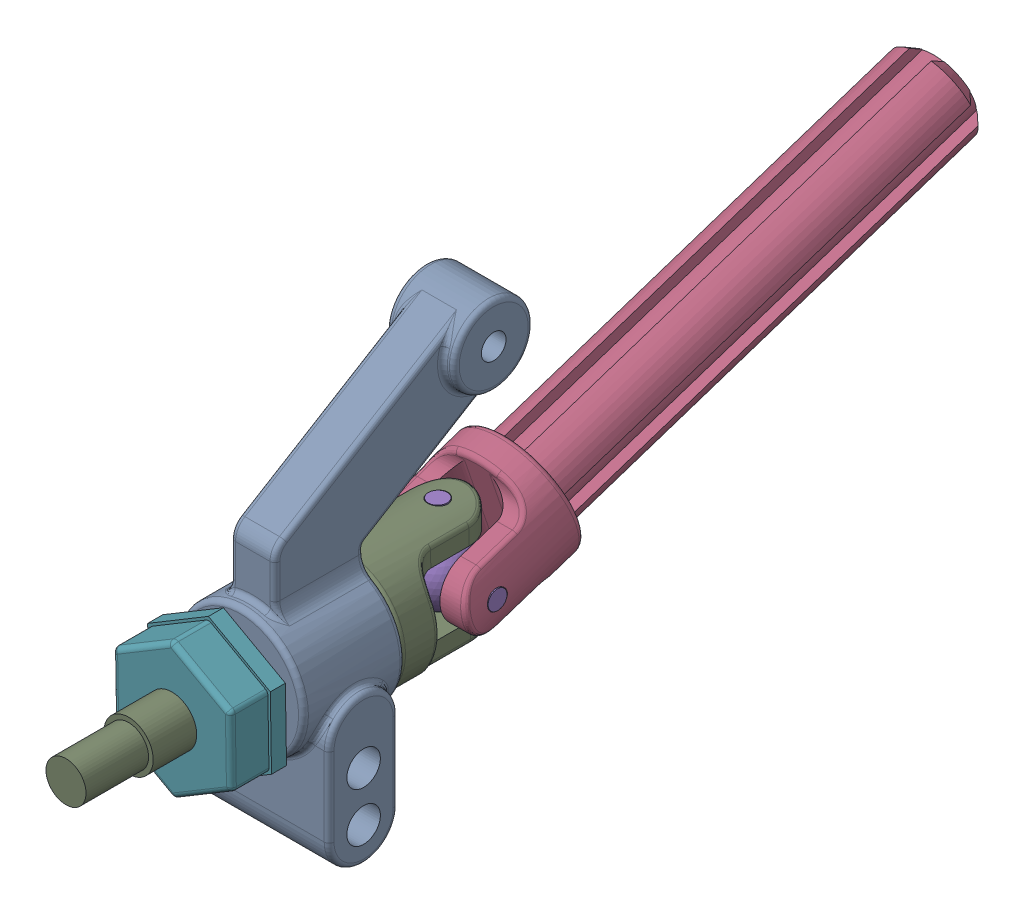
SolidWorks assembly rear spindle(Default-_flexible1), configuration Default. Lengths in mm.
Overall size (14.8 39 90.91).
9 component instances, 8 part files, 0 mates.
Components (placement in the parent):
- 3752-1: 3752 [Default] at origin size (14.8 39 26.3)
- 1675-1: 1675 [Default] at (0 0 -3.65) x (0.905715 0.423888 0) z (0 0 1) size (8 8 3)
- 1675-2: 1675 [Default] at (0 0 3.65) x (0.854501 -0.519449 0) z (0 0 1) size (8 8 3)
- 1951A-1: 1951A [Default] at (0 2.7756 -23.4548) x (0.017463 -0.949691 -0.312701) z (0 -0.312748 0.949836) size (12 12 57)
- 1951B-1: 1951B [Default] at (0 0 -15.025) x (-0.999848 -0.016587 -0.005462) z (-0.005461 -0.000091 0.999985) size (12 12 6.5)
- 2754-1: 2754 [Default] at (0 0 7.2) x (-0.016588 0.999862 0) z (0.170296 0.002825 0.985389) size (9.65 1.98 1.98)
- 3654-1: 3654 [Default] at (0 0 8.2287) x (0.016588 -0.999862 0) z (0 0 1) size (14.37 12.45 5.84)
- 1985-1: 1985 [Default] at (0 0 5.4) x (-0.754666 -0.656109 0) z (0 0 1) size (8 8 0.5)
- 1951C-1: 1951C [Default] at (0 0 -5.15) x (-0.999862 -0.016588 0) z (0 0 -1) size (12 12 40.95)
